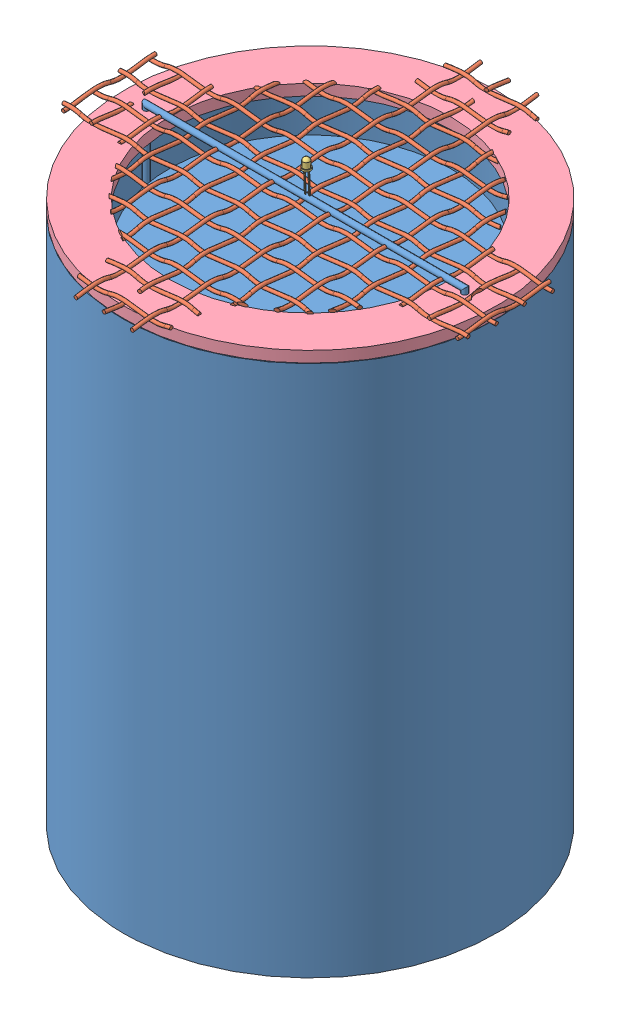
SolidWorks assembly SMFC_Assemb, configuration Default. Lengths in mm.
Overall size (337.01 263.08 337.01).
4 component instances, 4 part files, 0 mates.
Components (placement in the parent):
- UbiComp_SMFC-1: UbiComp_SMFC [Default] at (-89.0733 -44.8006 -142.8018) size (337.01 248.07 337.01)
- WireMesh-3: WireMesh [Default] at (43.1839 200.9231 -2.6065) size (299.86 3.51 300.02)
- 3mmLEDRed-1: 3mmLEDRed [Default] at (-88.1632 215.7147 -140.2769) x (0.998217 0.016993 0.057212) z (-0.018116 0.999652 0.019175) size (3.7 3.7 16.6)
- CarbonFeltRing-1: CarbonFeltRing [Default] at (-89.2849 195.1553 -143.1134) size (168.3 5 168.3)
